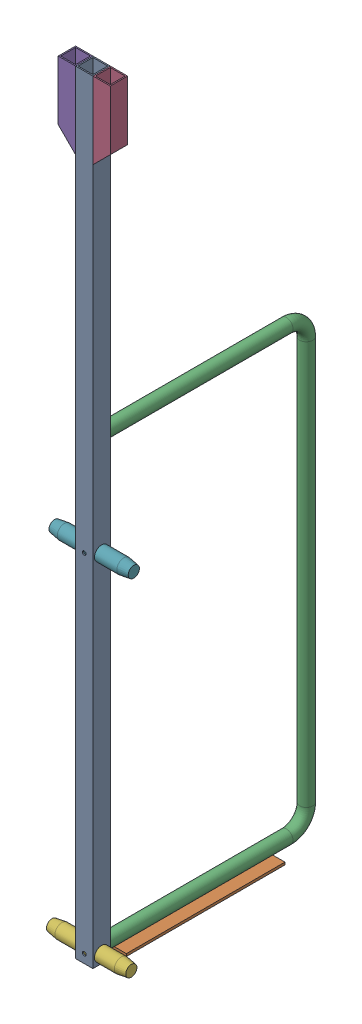
SolidWorks assembly FE-00001_ASM, configuration Default. Lengths in mm.
Overall size (209.55 1981.2 585.85).
7 component instances, 5 part files, 0 mates.
Components (placement in the parent):
- FE-00001-05-1: FE-00001-05 [Default] at origin size (44.45 1981.2 44.45)
- FE-00001-02-1: FE-00001-02 [Default] at (60.325 0 -69.85) x (0 0 -1) z (1 0 0) size (406.4 6.35 76.2)
- FE-00001-03-1: FE-00001-03 [Default] at (22.225 1158.113 -44.45) size (33.4 1168.46 541.4)
- FE-00001-01-1: FE-00001-01 [Default] at (44.45 1981.2 0) x (0 0 -1) z (-1 0 0) size (44.45 196.85 44.45)
- FE-00001-01-2: FE-00001-01 [Default] at (0 1981.2 -44.45) x (0 0 1) z (1 0 0) size (44.45 196.85 44.45)
- FE-00001-04-1: FE-00001-04 [Default] at (-82.55 22.225 -22.225) size (203.2 36.51 36.51)
- FE-00001-04-2: FE-00001-04 [Default] at (-76.2 911.225 -22.225) size (203.2 36.51 36.51)
